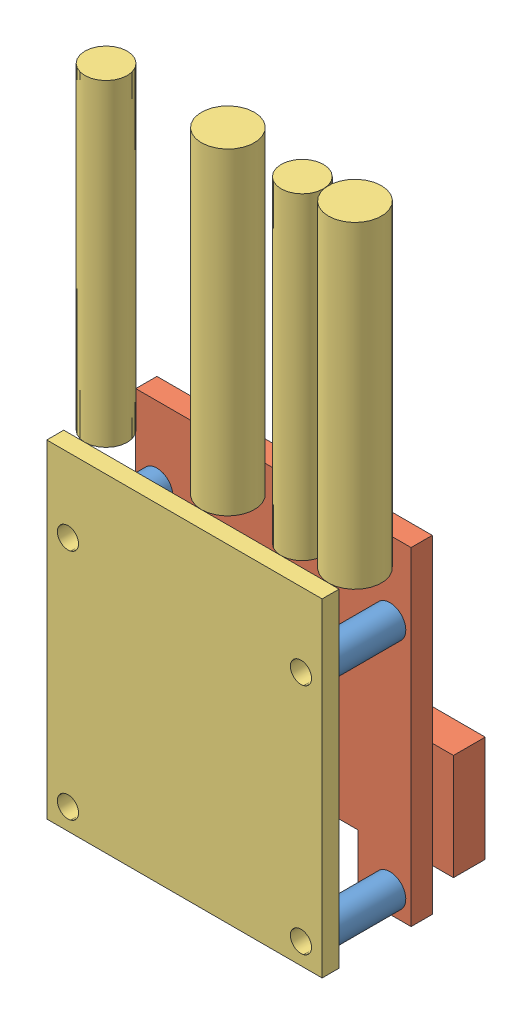
SolidWorks assembly FC_MatekF405WMN, configuration Default. Lengths in mm.
Overall size (28 61 18.85).
6 component instances, 3 part files, 12 mates.
Components (placement in the parent):
- FCScrew-1: FCScrew [Default] at (11 8.5 -4.2) x (-0.400084 -0.916479 0) z (0 0 1) size (3 3 6.8)
- MatekF405WMNFC-1: MatekF405WMNFC [Default] at (0 0 -7.6) x (-1 0 0) z (0 0 -1) size (28 31 5)
- MatekF405WMNPDB-1: MatekF405WMNPDB [Default] at origin size (27.5 61 12.05)
- FCScrew-2: FCScrew [Default] at (11 -13.5 -4.2) x (-0.99923 -0.039246 0) z (0 0 1) size (3 3 6.8)
- FCScrew-3: FCScrew [Default] at (-11 8.5 -4.2) x (-0.400084 -0.916479 0) z (0 0 1) size (3 3 6.8)
- FCScrew-4: FCScrew [Default] at (-11 -13.5 -4.2) x (-0.400084 -0.916479 0) z (0 0 1) size (3 3 6.8)
Mates (geometry in assembly coordinates):
- Совпадение4: coordinate: point of MatekF405WMNPDB-1
- Концентричный5: concentric aligned: cylinder of MatekF405WMNFC-1 through (-11 8.5 -7.6) axis (0 0 -1) radius 1; cylinder of MatekF405WMNPDB-1 through (-11 8.5 0.8) axis (0 0 -1) radius 1
- Концентричный6: concentric aligned: cylinder of MatekF405WMNFC-1 through (11 8.5 -7.6) axis (0 0 -1) radius 1; cylinder of MatekF405WMNPDB-1 through (11 8.5 0.8) axis (0 0 -1) radius 1
- Концентричный7: concentric aligned: cylinder of FCScrew-1 through (11 8.5 -0.8) axis (0 0 -1) radius 1; cylinder of MatekF405WMNFC-1 through (11 8.5 -7.6) axis (0 0 -1) radius 1
- Совпадение5: coincident anti-aligned: plane of FCScrew-1 through (11 8.5 -7.6) normal (0 0 -1); plane of MatekF405WMNFC-1 through (0 0 -7.6) normal (0 0 1)
- Совпадение6: coincident anti-aligned: plane of FCScrew-1 through (11 8.5 -0.8) normal (0 0 1); plane of MatekF405WMNPDB-1 through (0 0 -0.8) normal (0 0 -1)
- Концентричный8: concentric aligned: cylinder of MatekF405WMNFC-1 through (11 -13.5 -7.6) axis (0 0 -1) radius 1; cylinder of FCScrew-2 through (11 -13.5 -0.8) axis (0 0 -1) radius 1
- Совпадение7: coincident anti-aligned: plane of MatekF405WMNFC-1 through (0 0 -7.6) normal (0 0 1); plane of FCScrew-2 through (11 -13.5 -7.6) normal (0 0 -1)
- Совпадение8: coincident anti-aligned: plane of MatekF405WMNFC-1 through (0 0 -7.6) normal (0 0 1); plane of FCScrew-4 through (-11 -13.5 -7.6) normal (0 0 -1)
- Концентричный9: concentric aligned: cylinder of MatekF405WMNPDB-1 through (-11 -13.5 0.8) axis (0 0 -1) radius 1; cylinder of FCScrew-4 through (-11 -13.5 -0.8) axis (0 0 -1) radius 1
- Концентричный10: concentric aligned: cylinder of MatekF405WMNPDB-1 through (-11 8.5 0.8) axis (0 0 -1) radius 1; cylinder of FCScrew-3 through (-11 8.5 -0.8) axis (0 0 -1) radius 1
- Совпадение9: coincident anti-aligned: plane of MatekF405WMNFC-1 through (0 0 -7.6) normal (0 0 1); plane of FCScrew-3 through (-11 8.5 -7.6) normal (0 0 -1)
